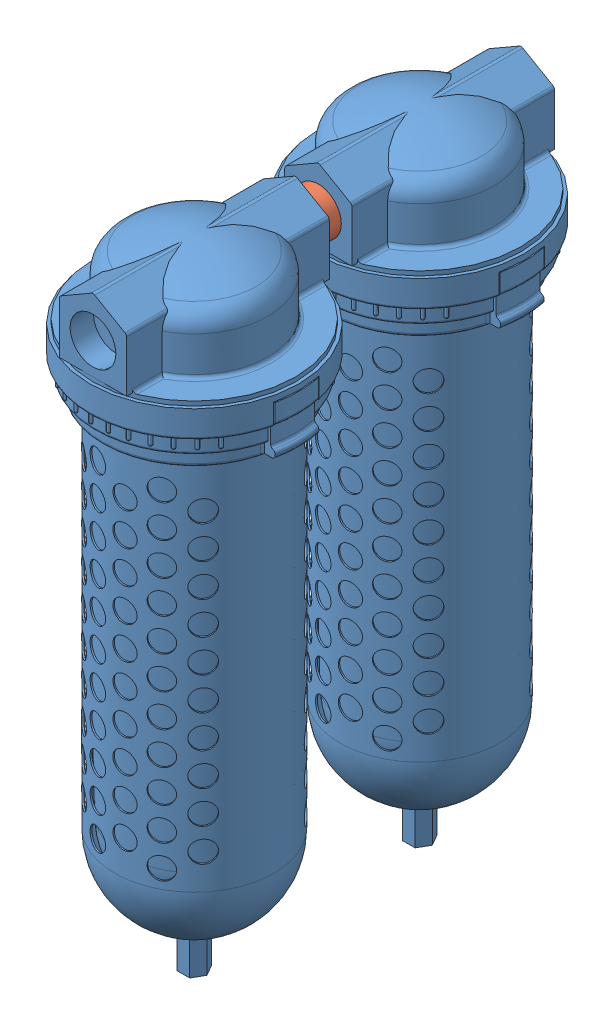
SolidWorks assembly ReadingTech_4P-150-P06-DC, configuration Default. Lengths in mm.
Overall size (121.86 369.43 252.73).
3 component instances, 2 part files, 3 mates.
Components (placement in the parent):
- ReadingTech_3P150P06F-1: ReadingTech_3P150P06F [Default] at (-32.8684 -216.9317 9.586) size (121.86 369.43 121.67)
- ReadingTech_3P150P06F-2: ReadingTech_3P150P06F [Default] at (-32.8684 -216.9317 -121.478) size (121.86 369.43 121.67)
- ReadingTech- 90,150cfm_connector_.75in-1: ReadingTech- 90,150cfm_connector_.75in [Default] at (-32.8684 172.0693 -49.342) x (1 0 0) z (0 1 0) size (26.67 13.21 26.67)
Mates (geometry in assembly coordinates):
- Coincident1: coincident anti-aligned: circle of ReadingTech_3P150P06F-2; circle of ReadingTech- 90,150cfm_connector_.75in-1
- Coincident2: coincident aligned: circle of ReadingTech_3P150P06F-1; circle of ReadingTech- 90,150cfm_connector_.75in-1
- Coincident3: coincident aligned: plane of ReadingTech_3P150P06F-1 through (-13.3104 184.7693 68.514) normal (1 0 0); plane of ReadingTech_3P150P06F-2 through (-13.3104 184.7693 -62.55) normal (1 0 0)
